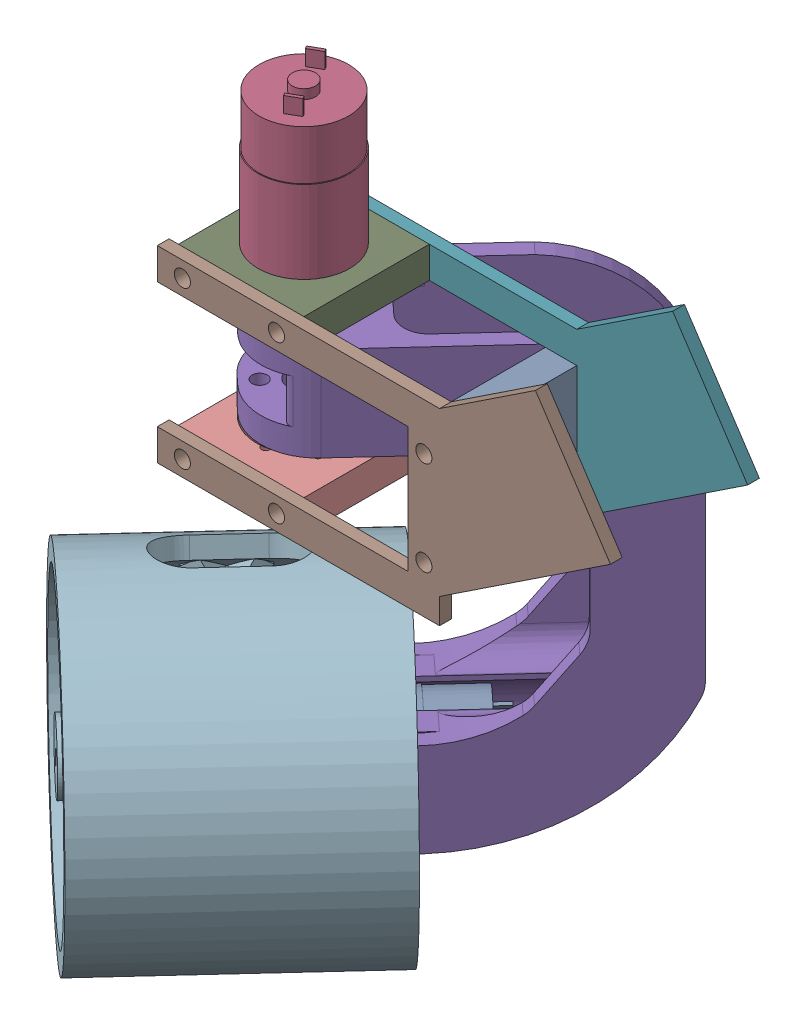
SolidWorks assembly Wheel_Assem, configuration Default. Lengths in mm.
Overall size (258.78 314.48 205.28).
13 component instances, 9 part files, 34 mates.
Components (placement in the parent):
- DC Motor-1: DC Motor [Default] at (23.2069 -270.668 -135.8073) x (0.637128 -0.5 0.586573) z (-0.367846 -0.866025 -0.338658) size (37 79.65 37)
- Motor Mount-1: Motor Mount [Default] at (3.1678 -289.718 -76.5403) x (0 1 0) z (-0.735692 0 -0.677317) size (38.1 3.17 50.8)
- Wheel Mount-1: Wheel Mount [Default] at (-38.5062 -251.618 -106.2764) x (0 -1 0) z (0.677317 0 -0.735692) size (38.1 50.8 6.35)
- DC Motor-2: DC Motor [Default] at (-13.3682 -39.0938 -96.08) x (0.5 0 0.866025) z (0.866025 0 -0.5) size (37 79.65 37)
- Wheel Join Whole-1: Wheel Join Whole [Default] at (-14.851 -251.618 -131.9704) x (0.677317 0 -0.735692) z (0.735692 0 0.677317) size (133.11 177.8 50.8)
- Shaft Coupler-1: Shaft Coupler [Default] at (-13.3682 -112.1438 -96.08) x (0.677317 0 -0.735692) z (0.735692 0 0.677317) size (38.1 11.43 38.1)
- frame_standin-1: frame_standin [Default] at (-42.5782 -105.7938 -126.2425) size (183.5 101.96 4.76)
- frame_standin-2: frame_standin [Default] at (-42.5782 -105.7938 -70.68) size (183.5 101.96 4.76)
- Frame_Join_A-1: Frame_Join_A [Default] at (-38.7682 -105.7938 -121.48) x (1 0 0) z (0 -1 0) size (50.8 50.8 12.7)
- Frame_Join_A-4: Frame_Join_A [Default] at (-38.7682 -156.5938 -70.68) x (1 0 0) z (0 1 0) size (50.8 50.8 12.7)
- Shaft Coupler-2: Shaft Coupler [Default] at (-13.3682 -150.2438 -96.08) x (0.735692 0 0.677317) z (0.677317 0 -0.735692) size (38.1 11.43 38.1)
- Wheel Interior-1: Wheel Interior [Default] at (7.2764 -270.668 -118.5039) x (0.715416 0.233153 0.65865) z (-0.677317 0 0.735692) size (127 127 101.6)
- Frame_Join_B-1: Frame_Join_B [Default] at (59.0218 -156.5938 -121.48) size (12.7 50.8 50.8)
Mates (geometry in assembly coordinates):
- Coincident1: coincident anti-aligned: plane of DC Motor-1 through (-13.3682 -270.668 -96.08) normal (-0.677317 0 0.735692); plane of Motor Mount-1 through (5.3183 -289.718 -78.8762) normal (0.677317 0 -0.735692)
- Concentric1: concentric aligned: cylinder of DC Motor-1 through (-0.4193 -284.0914 -98.7027) axis (-0.677317 0 0.735692) radius 1.5; cylinder of Motor Mount-1 through (-7.6666 -284.0914 -90.8308) axis (-0.677317 0 0.735692) radius 1.65
- Concentric2: concentric aligned: circle of DC Motor-1; cylinder of Motor Mount-1 through (-19.0698 -284.0914 -101.3292) axis (-0.677317 0 0.735692) radius 1.65
- Coincident2: coincident anti-aligned: plane of Motor Mount-1 through (3.1678 -289.718 -76.5403) normal (-0.677317 0 0.735692); plane of Wheel Mount-1 through (-29.5336 -283.368 -106.6471) normal (0.677317 0 -0.735692)
- Concentric3: concentric aligned: cylinder of Motor Mount-1 through (-27.3832 -283.368 -108.9829) axis (-0.677317 0 0.735692) radius 3.2639; cylinder of Wheel Mount-1 through (-31.6841 -283.368 -104.3112) axis (-0.677317 0 0.735692) radius 3.2639
- Concentric4: concentric aligned: cylinder of Motor Mount-1 through (0.6467 -257.968 -83.1771) axis (-0.677317 0 0.735692) radius 3.2639; cylinder of Wheel Mount-1 through (-3.6543 -257.968 -78.5055) axis (-0.677317 0 0.735692) radius 3.2639
- Coincident20: coincident anti-aligned: plane of Motor Mount-1 through (5.3183 -289.718 -78.8762) normal (0.677317 0 -0.735692); plane of Wheel Join Whole-1 through (-13.3682 -270.668 -96.08) normal (-0.677317 0 0.735692)
- Coincident21: coincident anti-aligned: circle of Motor Mount-1; cylinder of Wheel Join Whole-1 through (-1.5774 -257.968 -137.0127) axis (-0.677317 0 0.735692) radius 3.2639
- Coincident22: coincident anti-aligned: circle of Wheel Mount-1; cylinder of Wheel Join Whole-1 through (26.4525 -283.368 -111.207) axis (-0.677317 0 0.735692) radius 3.2639
- Coincident23: coincident anti-aligned: plane of Wheel Join Whole-1 through (-5.8905 -112.1438 -132.328) normal (0 1 0); plane of Shaft Coupler-1 through (-13.3682 -112.1438 -96.08) normal (0 -1 0)
- Concentric5: concentric aligned: circle of Wheel Join Whole-1; circle of Shaft Coupler-1
- Concentric6: concentric anti-aligned: circle of Wheel Join Whole-1; cylinder of Shaft Coupler-1 through (-4.7663 -108.9688 -105.4233) axis (0 -1 0) radius 3.9402
- Concentric7: concentric aligned: circle of DC Motor-2; cylinder of Shaft Coupler-1 through (-13.3682 -100.7138 -96.08) axis (0 -1 0) radius 8.2843
- Coincident24: coincident anti-aligned: plane of frame_standin-2 through (-42.5782 -105.7938 -70.68) normal (0 0 -1); plane of Frame_Join_A-1 through (-38.7682 -105.7938 -70.68) normal (0 0 1)
- Coincident25: coincident anti-aligned: plane of frame_standin-1 through (-42.5782 -105.7938 -121.48) normal (0 0 1); plane of Frame_Join_A-1 through (-38.7682 -105.7938 -121.48) normal (0 0 -1)
- Concentric9: concentric aligned: cylinder of frame_standin-1 through (5.6818 -99.4438 -121.48) axis (0 0 -1) radius 3.2639; cylinder of frame_standin-2 through (5.6818 -99.4438 -65.9175) axis (0 0 -1) radius 3.2639
- Concentric12: concentric aligned: cylinder of Shaft Coupler-1 through (-13.3682 -100.7138 -96.08) axis (0 -1 0) radius 5.1093; cylinder of Frame_Join_A-1 through (-13.3682 -93.0938 -96.08) axis (0 -1 0) radius 3.175
- Concentric13: concentric anti-aligned: cylinder of frame_standin-2 through (-32.4182 -99.4438 -65.9175) axis (0 0 -1) radius 3.2639; cylinder of Frame_Join_A-1 through (-32.4182 -99.4438 -83.38) axis (0 0 1) radius 3.2639
- Concentric14: concentric anti-aligned: cylinder of frame_standin-2 through (5.6818 -99.4438 -65.9175) axis (0 0 -1) radius 3.2639; cylinder of Frame_Join_A-1 through (5.6818 -99.4438 -83.38) axis (0 0 1) radius 3.2639
- Concentric15: concentric aligned: cylinder of frame_standin-1 through (-32.4182 -99.4438 -121.48) axis (0 0 -1) radius 3.2639; cylinder of Frame_Join_A-1 through (-32.4182 -99.4438 -108.78) axis (0 0 -1) radius 3.2639
- Coincident32: coincident anti-aligned: plane of frame_standin-1 through (-42.5782 -105.7938 -121.48) normal (0 0 1); plane of Frame_Join_A-4 through (-38.7682 -156.5938 -121.48) normal (0 0 -1)
- Coincident33: coincident aligned: circle of frame_standin-2; cylinder of Frame_Join_A-4 through (5.6818 -162.9438 -83.38) axis (0 0 1) radius 3.2639
- Coincident34: coincident aligned: circle of frame_standin-2; cylinder of Frame_Join_A-4 through (-32.4182 -162.9438 -83.38) axis (0 0 1) radius 3.2639
- Width2: width aligned: plane of Wheel Join Whole-1 through (-5.8905 -112.1438 -132.328) normal (0 1 0); plane of Frame_Join_A-4 through (4.8271 -150.2438 -143.9692) normal (0 -1 0); plane of Wheel Join Whole-1 through (-38.7682 -156.5938 -121.48) normal (0 1 0); plane of Frame_Join_A-1 through (-38.7682 -105.7938 -70.68) normal (0 -1 0)
- Coincident35: coincident anti-aligned: plane of Wheel Join Whole-1 through (4.8271 -150.2438 -143.9692) normal (0 -1 0); plane of Shaft Coupler-2 through (-13.3682 -150.2438 -96.08) normal (0 1 0)
- Concentric16: concentric anti-aligned: circle of Wheel Join Whole-1; cylinder of Shaft Coupler-2 through (-13.3682 -161.6738 -96.08) axis (0 1 0) radius 5.1093
- Concentric18: concentric aligned: cylinder of Wheel Join Whole-1 through (-4.025 -168.2043 -87.4781) axis (0 1 0) radius 3.0386; cylinder of Shaft Coupler-2 through (-4.025 -153.4188 -87.4781) axis (0 1 0) radius 3.9402
- Coincident39: coincident anti-aligned: plane of DC Motor-2 through (-13.3682 -93.0938 -96.08) normal (0 -1 0); plane of Frame_Join_A-1 through (-38.7682 -93.0938 -70.68) normal (0 1 0)
- Concentric20: concentric aligned: cylinder of DC Motor-2 through (0.0552 -82.3938 -103.83) axis (0 -1 0) radius 1.5; circle of Frame_Join_A-1
- Concentric26: concentric aligned: cylinder of DC Motor-1 through (-26.4405 -270.668 -81.8812) axis (0.677317 0 -0.735692) radius 3; cylinder of Wheel Interior-1 through (-61.539 -270.668 -43.7576) axis (0.677317 0 -0.735692) radius 3.302
- Distance1: distance = 3.175 mm anti-aligned: plane of Wheel Interior-1 through (-21.9702 -270.668 -86.7367) normal (0.677317 0 -0.735692); plane of Wheel Mount-1 through (-38.5062 -251.618 -106.2764) normal (-0.677317 0 0.735692)
- Coincident46: coincident anti-aligned: plane of frame_standin-2 through (-42.5782 -105.7938 -70.68) normal (0 0 -1); plane of Frame_Join_B-1 through (59.0218 -156.5938 -70.68) normal (0 0 1)
- Coincident47: coincident aligned: cylinder of frame_standin-2 through (65.3718 -112.1438 -70.681) axis (0 0 1) radius 3.2639; circle of Frame_Join_B-1
- Concentric27: concentric aligned: cylinder of frame_standin-2 through (65.3718 -150.2438 -70.681) axis (0 0 1) radius 3.2639; cylinder of Frame_Join_B-1 through (65.3718 -150.2438 -89.73) axis (0 0 1) radius 3.2639
